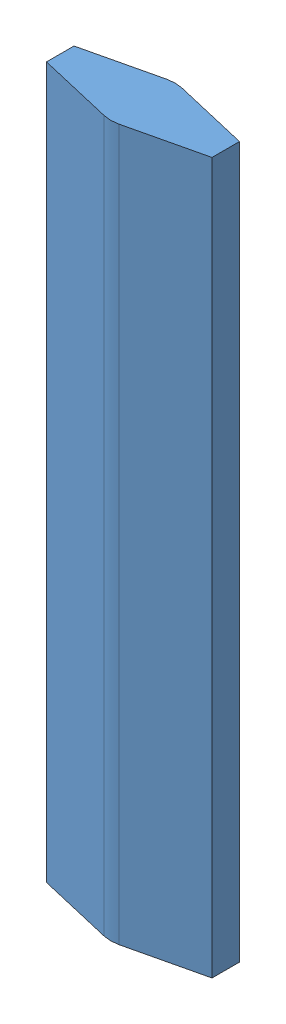
SolidWorks assembly String-III, configuration 默认. Lengths in mm.
Overall size (538.95 1520 404.36).
161 component instances, 6 part files, 3 mates.
Components (placement in the parent):
- StringBox-III-1: StringBox-III [默认] at (25.091 -857.2069 1520) size (354 1520 138)
- Unit-III-1: Unit-III [默认] at (25.091 -850.6069 1520) size (538.95 85.58 404.36)
  - OuterShell-III-1: OuterShell-III [默认] at origin size (538.95 73.59 404.36)
  - InnerUnit-1: InnerUnit [默认] at (-1.9481 30.6195 80) x (1 0 0) z (0 0 -1) size (102 85 103.7)
    - BEGeDet-2: BEGeDet [默认] at (1.9481 14.6195 80) x (1 0 0) z (0 0 -1) size (80 40 80)
    - InnerShell-3: InnerShell [默认] at (1.9481 -36.3805 80) size (102 61 102)
    - Electronics-1: Electronics [默认] at (1.9481 24.7195 80) x (-1 0 0) z (0 0 1) size (21.21 85 103.7)
  - SiPMArray-1: SiPMArray [默认] at (165 35.3248 0) size (10.4 81 40.4)
  - SiPMArray-2: SiPMArray [默认] at (-165 35.3248 0) x (-1 0 0) z (0 0 -1) size (10.4 81 40.4)
- Unit-III-2: Unit-III [默认] at (25.091 -778.6069 1520) size (538.95 85.58 404.36)
  - OuterShell-III-1: OuterShell-III [默认] at origin size (538.95 73.59 404.36)
  - InnerUnit-1: InnerUnit [默认] at (-1.9481 30.6195 80) x (1 0 0) z (0 0 -1) size (102 85 103.7)
    - BEGeDet-2: BEGeDet [默认] at (1.9481 14.6195 80) x (1 0 0) z (0 0 -1) size (80 40 80)
    - InnerShell-3: InnerShell [默认] at (1.9481 -36.3805 80) size (102 61 102)
    - Electronics-1: Electronics [默认] at (1.9481 24.7195 80) x (-1 0 0) z (0 0 1) size (21.21 85 103.7)
  - SiPMArray-1: SiPMArray [默认] at (165 35.3248 0) size (10.4 81 40.4)
  - SiPMArray-2: SiPMArray [默认] at (-165 35.3248 0) x (-1 0 0) z (0 0 -1) size (10.4 81 40.4)
- Unit-III-3: Unit-III [默认] at (25.091 -706.6069 1520) size (538.95 85.58 404.36)
  - OuterShell-III-1: OuterShell-III [默认] at origin size (538.95 73.59 404.36)
  - InnerUnit-1: InnerUnit [默认] at (-1.9481 30.6195 80) x (1 0 0) z (0 0 -1) size (102 85 103.7)
    - BEGeDet-2: BEGeDet [默认] at (1.9481 14.6195 80) x (1 0 0) z (0 0 -1) size (80 40 80)
    - InnerShell-3: InnerShell [默认] at (1.9481 -36.3805 80) size (102 61 102)
    - Electronics-1: Electronics [默认] at (1.9481 24.7195 80) x (-1 0 0) z (0 0 1) size (21.21 85 103.7)
  - SiPMArray-1: SiPMArray [默认] at (165 35.3248 0) size (10.4 81 40.4)
  - SiPMArray-2: SiPMArray [默认] at (-165 35.3248 0) x (-1 0 0) z (0 0 -1) size (10.4 81 40.4)
- Unit-III-4: Unit-III [默认] at (25.091 -634.6069 1520) size (538.95 85.58 404.36)
  - OuterShell-III-1: OuterShell-III [默认] at origin size (538.95 73.59 404.36)
  - InnerUnit-1: InnerUnit [默认] at (-1.9481 30.6195 80) x (1 0 0) z (0 0 -1) size (102 85 103.7)
    - BEGeDet-2: BEGeDet [默认] at (1.9481 14.6195 80) x (1 0 0) z (0 0 -1) size (80 40 80)
    - InnerShell-3: InnerShell [默认] at (1.9481 -36.3805 80) size (102 61 102)
    - Electronics-1: Electronics [默认] at (1.9481 24.7195 80) x (-1 0 0) z (0 0 1) size (21.21 85 103.7)
  - SiPMArray-1: SiPMArray [默认] at (165 35.3248 0) size (10.4 81 40.4)
  - SiPMArray-2: SiPMArray [默认] at (-165 35.3248 0) x (-1 0 0) z (0 0 -1) size (10.4 81 40.4)
- Unit-III-5: Unit-III [默认] at (25.091 -562.6069 1520) size (538.95 85.58 404.36)
  - OuterShell-III-1: OuterShell-III [默认] at origin size (538.95 73.59 404.36)
  - InnerUnit-1: InnerUnit [默认] at (-1.9481 30.6195 80) x (1 0 0) z (0 0 -1) size (102 85 103.7)
    - BEGeDet-2: BEGeDet [默认] at (1.9481 14.6195 80) x (1 0 0) z (0 0 -1) size (80 40 80)
    - InnerShell-3: InnerShell [默认] at (1.9481 -36.3805 80) size (102 61 102)
    - Electronics-1: Electronics [默认] at (1.9481 24.7195 80) x (-1 0 0) z (0 0 1) size (21.21 85 103.7)
  - SiPMArray-1: SiPMArray [默认] at (165 35.3248 0) size (10.4 81 40.4)
  - SiPMArray-2: SiPMArray [默认] at (-165 35.3248 0) x (-1 0 0) z (0 0 -1) size (10.4 81 40.4)
- Unit-III-6: Unit-III [默认] at (25.091 -490.6069 1520) size (538.95 85.58 404.36)
  - OuterShell-III-1: OuterShell-III [默认] at origin size (538.95 73.59 404.36)
  - InnerUnit-1: InnerUnit [默认] at (-1.9481 30.6195 80) x (1 0 0) z (0 0 -1) size (102 85 103.7)
    - BEGeDet-2: BEGeDet [默认] at (1.9481 14.6195 80) x (1 0 0) z (0 0 -1) size (80 40 80)
    - InnerShell-3: InnerShell [默认] at (1.9481 -36.3805 80) size (102 61 102)
    - Electronics-1: Electronics [默认] at (1.9481 24.7195 80) x (-1 0 0) z (0 0 1) size (21.21 85 103.7)
  - SiPMArray-1: SiPMArray [默认] at (165 35.3248 0) size (10.4 81 40.4)
  - SiPMArray-2: SiPMArray [默认] at (-165 35.3248 0) x (-1 0 0) z (0 0 -1) size (10.4 81 40.4)
- Unit-III-7: Unit-III [默认] at (25.091 -418.6069 1520) size (538.95 85.58 404.36)
  - OuterShell-III-1: OuterShell-III [默认] at origin size (538.95 73.59 404.36)
  - InnerUnit-1: InnerUnit [默认] at (-1.9481 30.6195 80) x (1 0 0) z (0 0 -1) size (102 85 103.7)
    - BEGeDet-2: BEGeDet [默认] at (1.9481 14.6195 80) x (1 0 0) z (0 0 -1) size (80 40 80)
    - InnerShell-3: InnerShell [默认] at (1.9481 -36.3805 80) size (102 61 102)
    - Electronics-1: Electronics [默认] at (1.9481 24.7195 80) x (-1 0 0) z (0 0 1) size (21.21 85 103.7)
  - SiPMArray-1: SiPMArray [默认] at (165 35.3248 0) size (10.4 81 40.4)
  - SiPMArray-2: SiPMArray [默认] at (-165 35.3248 0) x (-1 0 0) z (0 0 -1) size (10.4 81 40.4)
- Unit-III-8: Unit-III [默认] at (25.091 -346.6069 1520) size (538.95 85.58 404.36)
  - OuterShell-III-1: OuterShell-III [默认] at origin size (538.95 73.59 404.36)
  - InnerUnit-1: InnerUnit [默认] at (-1.9481 30.6195 80) x (1 0 0) z (0 0 -1) size (102 85 103.7)
    - BEGeDet-2: BEGeDet [默认] at (1.9481 14.6195 80) x (1 0 0) z (0 0 -1) size (80 40 80)
    - InnerShell-3: InnerShell [默认] at (1.9481 -36.3805 80) size (102 61 102)
    - Electronics-1: Electronics [默认] at (1.9481 24.7195 80) x (-1 0 0) z (0 0 1) size (21.21 85 103.7)
  - SiPMArray-1: SiPMArray [默认] at (165 35.3248 0) size (10.4 81 40.4)
  - SiPMArray-2: SiPMArray [默认] at (-165 35.3248 0) x (-1 0 0) z (0 0 -1) size (10.4 81 40.4)
- Unit-III-9: Unit-III [默认] at (25.091 -274.6069 1520) size (538.95 85.58 404.36)
  - OuterShell-III-1: OuterShell-III [默认] at origin size (538.95 73.59 404.36)
  - InnerUnit-1: InnerUnit [默认] at (-1.9481 30.6195 80) x (1 0 0) z (0 0 -1) size (102 85 103.7)
    - BEGeDet-2: BEGeDet [默认] at (1.9481 14.6195 80) x (1 0 0) z (0 0 -1) size (80 40 80)
    - InnerShell-3: InnerShell [默认] at (1.9481 -36.3805 80) size (102 61 102)
    - Electronics-1: Electronics [默认] at (1.9481 24.7195 80) x (-1 0 0) z (0 0 1) size (21.21 85 103.7)
  - SiPMArray-1: SiPMArray [默认] at (165 35.3248 0) size (10.4 81 40.4)
  - SiPMArray-2: SiPMArray [默认] at (-165 35.3248 0) x (-1 0 0) z (0 0 -1) size (10.4 81 40.4)
- Unit-III-10: Unit-III [默认] at (25.091 -202.6069 1520) size (538.95 85.58 404.36)
  - OuterShell-III-1: OuterShell-III [默认] at origin size (538.95 73.59 404.36)
  - InnerUnit-1: InnerUnit [默认] at (-1.9481 30.6195 80) x (1 0 0) z (0 0 -1) size (102 85 103.7)
    - BEGeDet-2: BEGeDet [默认] at (1.9481 14.6195 80) x (1 0 0) z (0 0 -1) size (80 40 80)
    - InnerShell-3: InnerShell [默认] at (1.9481 -36.3805 80) size (102 61 102)
    - Electronics-1: Electronics [默认] at (1.9481 24.7195 80) x (-1 0 0) z (0 0 1) size (21.21 85 103.7)
  - SiPMArray-1: SiPMArray [默认] at (165 35.3248 0) size (10.4 81 40.4)
  - SiPMArray-2: SiPMArray [默认] at (-165 35.3248 0) x (-1 0 0) z (0 0 -1) size (10.4 81 40.4)
- Unit-III-11: Unit-III [默认] at (25.091 -130.6069 1520) size (538.95 85.58 404.36)
  - OuterShell-III-1: OuterShell-III [默认] at origin size (538.95 73.59 404.36)
  - InnerUnit-1: InnerUnit [默认] at (-1.9481 30.6195 80) x (1 0 0) z (0 0 -1) size (102 85 103.7)
    - BEGeDet-2: BEGeDet [默认] at (1.9481 14.6195 80) x (1 0 0) z (0 0 -1) size (80 40 80)
    - InnerShell-3: InnerShell [默认] at (1.9481 -36.3805 80) size (102 61 102)
    - Electronics-1: Electronics [默认] at (1.9481 24.7195 80) x (-1 0 0) z (0 0 1) size (21.21 85 103.7)
  - SiPMArray-1: SiPMArray [默认] at (165 35.3248 0) size (10.4 81 40.4)
  - SiPMArray-2: SiPMArray [默认] at (-165 35.3248 0) x (-1 0 0) z (0 0 -1) size (10.4 81 40.4)
- Unit-III-12: Unit-III [默认] at (25.091 -58.6069 1520) size (538.95 85.58 404.36)
  - OuterShell-III-1: OuterShell-III [默认] at origin size (538.95 73.59 404.36)
  - InnerUnit-1: InnerUnit [默认] at (-1.9481 30.6195 80) x (1 0 0) z (0 0 -1) size (102 85 103.7)
    - BEGeDet-2: BEGeDet [默认] at (1.9481 14.6195 80) x (1 0 0) z (0 0 -1) size (80 40 80)
    - InnerShell-3: InnerShell [默认] at (1.9481 -36.3805 80) size (102 61 102)
    - Electronics-1: Electronics [默认] at (1.9481 24.7195 80) x (-1 0 0) z (0 0 1) size (21.21 85 103.7)
  - SiPMArray-1: SiPMArray [默认] at (165 35.3248 0) size (10.4 81 40.4)
  - SiPMArray-2: SiPMArray [默认] at (-165 35.3248 0) x (-1 0 0) z (0 0 -1) size (10.4 81 40.4)
- Unit-III-13: Unit-III [默认] at (25.091 13.3931 1520) size (538.95 85.58 404.36)
  - OuterShell-III-1: OuterShell-III [默认] at origin size (538.95 73.59 404.36)
  - InnerUnit-1: InnerUnit [默认] at (-1.9481 30.6195 80) x (1 0 0) z (0 0 -1) size (102 85 103.7)
    - BEGeDet-2: BEGeDet [默认] at (1.9481 14.6195 80) x (1 0 0) z (0 0 -1) size (80 40 80)
    - InnerShell-3: InnerShell [默认] at (1.9481 -36.3805 80) size (102 61 102)
    - Electronics-1: Electronics [默认] at (1.9481 24.7195 80) x (-1 0 0) z (0 0 1) size (21.21 85 103.7)
  - SiPMArray-1: SiPMArray [默认] at (165 35.3248 0) size (10.4 81 40.4)
  - SiPMArray-2: SiPMArray [默认] at (-165 35.3248 0) x (-1 0 0) z (0 0 -1) size (10.4 81 40.4)
- Unit-III-14: Unit-III [默认] at (25.091 85.3931 1520) size (538.95 85.58 404.36)
  - OuterShell-III-1: OuterShell-III [默认] at origin size (538.95 73.59 404.36)
  - InnerUnit-1: InnerUnit [默认] at (-1.9481 30.6195 80) x (1 0 0) z (0 0 -1) size (102 85 103.7)
    - BEGeDet-2: BEGeDet [默认] at (1.9481 14.6195 80) x (1 0 0) z (0 0 -1) size (80 40 80)
    - InnerShell-3: InnerShell [默认] at (1.9481 -36.3805 80) size (102 61 102)
    - Electronics-1: Electronics [默认] at (1.9481 24.7195 80) x (-1 0 0) z (0 0 1) size (21.21 85 103.7)
  - SiPMArray-1: SiPMArray [默认] at (165 35.3248 0) size (10.4 81 40.4)
  - SiPMArray-2: SiPMArray [默认] at (-165 35.3248 0) x (-1 0 0) z (0 0 -1) size (10.4 81 40.4)
- Unit-III-15: Unit-III [默认] at (25.091 157.3931 1520) size (538.95 85.58 404.36)
  - OuterShell-III-1: OuterShell-III [默认] at origin size (538.95 73.59 404.36)
  - InnerUnit-1: InnerUnit [默认] at (-1.9481 30.6195 80) x (1 0 0) z (0 0 -1) size (102 85 103.7)
    - BEGeDet-2: BEGeDet [默认] at (1.9481 14.6195 80) x (1 0 0) z (0 0 -1) size (80 40 80)
    - InnerShell-3: InnerShell [默认] at (1.9481 -36.3805 80) size (102 61 102)
    - Electronics-1: Electronics [默认] at (1.9481 24.7195 80) x (-1 0 0) z (0 0 1) size (21.21 85 103.7)
  - SiPMArray-1: SiPMArray [默认] at (165 35.3248 0) size (10.4 81 40.4)
  - SiPMArray-2: SiPMArray [默认] at (-165 35.3248 0) x (-1 0 0) z (0 0 -1) size (10.4 81 40.4)
- Unit-III-16: Unit-III [默认] at (25.091 229.3931 1520) size (538.95 85.58 404.36)
  - OuterShell-III-1: OuterShell-III [默认] at origin size (538.95 73.59 404.36)
  - InnerUnit-1: InnerUnit [默认] at (-1.9481 30.6195 80) x (1 0 0) z (0 0 -1) size (102 85 103.7)
    - BEGeDet-2: BEGeDet [默认] at (1.9481 14.6195 80) x (1 0 0) z (0 0 -1) size (80 40 80)
    - InnerShell-3: InnerShell [默认] at (1.9481 -36.3805 80) size (102 61 102)
    - Electronics-1: Electronics [默认] at (1.9481 24.7195 80) x (-1 0 0) z (0 0 1) size (21.21 85 103.7)
  - SiPMArray-1: SiPMArray [默认] at (165 35.3248 0) size (10.4 81 40.4)
  - SiPMArray-2: SiPMArray [默认] at (-165 35.3248 0) x (-1 0 0) z (0 0 -1) size (10.4 81 40.4)
- Unit-III-17: Unit-III [默认] at (25.091 301.3931 1520) size (538.95 85.58 404.36)
  - OuterShell-III-1: OuterShell-III [默认] at origin size (538.95 73.59 404.36)
  - InnerUnit-1: InnerUnit [默认] at (-1.9481 30.6195 80) x (1 0 0) z (0 0 -1) size (102 85 103.7)
    - BEGeDet-2: BEGeDet [默认] at (1.9481 14.6195 80) x (1 0 0) z (0 0 -1) size (80 40 80)
    - InnerShell-3: InnerShell [默认] at (1.9481 -36.3805 80) size (102 61 102)
    - Electronics-1: Electronics [默认] at (1.9481 24.7195 80) x (-1 0 0) z (0 0 1) size (21.21 85 103.7)
  - SiPMArray-1: SiPMArray [默认] at (165 35.3248 0) size (10.4 81 40.4)
  - SiPMArray-2: SiPMArray [默认] at (-165 35.3248 0) x (-1 0 0) z (0 0 -1) size (10.4 81 40.4)
- Unit-III-18: Unit-III [默认] at (25.091 373.3931 1520) size (538.95 85.58 404.36)
  - OuterShell-III-1: OuterShell-III [默认] at origin size (538.95 73.59 404.36)
  - InnerUnit-1: InnerUnit [默认] at (-1.9481 30.6195 80) x (1 0 0) z (0 0 -1) size (102 85 103.7)
    - BEGeDet-2: BEGeDet [默认] at (1.9481 14.6195 80) x (1 0 0) z (0 0 -1) size (80 40 80)
    - InnerShell-3: InnerShell [默认] at (1.9481 -36.3805 80) size (102 61 102)
    - Electronics-1: Electronics [默认] at (1.9481 24.7195 80) x (-1 0 0) z (0 0 1) size (21.21 85 103.7)
  - SiPMArray-1: SiPMArray [默认] at (165 35.3248 0) size (10.4 81 40.4)
  - SiPMArray-2: SiPMArray [默认] at (-165 35.3248 0) x (-1 0 0) z (0 0 -1) size (10.4 81 40.4)
- Unit-III-19: Unit-III [默认] at (25.091 445.3931 1520) size (538.95 85.58 404.36)
  - OuterShell-III-1: OuterShell-III [默认] at origin size (538.95 73.59 404.36)
  - InnerUnit-1: InnerUnit [默认] at (-1.9481 30.6195 80) x (1 0 0) z (0 0 -1) size (102 85 103.7)
    - BEGeDet-2: BEGeDet [默认] at (1.9481 14.6195 80) x (1 0 0) z (0 0 -1) size (80 40 80)
    - InnerShell-3: InnerShell [默认] at (1.9481 -36.3805 80) size (102 61 102)
    - Electronics-1: Electronics [默认] at (1.9481 24.7195 80) x (-1 0 0) z (0 0 1) size (21.21 85 103.7)
  - SiPMArray-1: SiPMArray [默认] at (165 35.3248 0) size (10.4 81 40.4)
  - SiPMArray-2: SiPMArray [默认] at (-165 35.3248 0) x (-1 0 0) z (0 0 -1) size (10.4 81 40.4)
- Unit-III-20: Unit-III [默认] at (25.091 517.3931 1520) size (538.95 85.58 404.36)
  - OuterShell-III-1: OuterShell-III [默认] at origin size (538.95 73.59 404.36)
  - InnerUnit-1: InnerUnit [默认] at (-1.9481 30.6195 80) x (1 0 0) z (0 0 -1) size (102 85 103.7)
    - BEGeDet-2: BEGeDet [默认] at (1.9481 14.6195 80) x (1 0 0) z (0 0 -1) size (80 40 80)
    - InnerShell-3: InnerShell [默认] at (1.9481 -36.3805 80) size (102 61 102)
    - Electronics-1: Electronics [默认] at (1.9481 24.7195 80) x (-1 0 0) z (0 0 1) size (21.21 85 103.7)
  - SiPMArray-1: SiPMArray [默认] at (165 35.3248 0) size (10.4 81 40.4)
  - SiPMArray-2: SiPMArray [默认] at (-165 35.3248 0) x (-1 0 0) z (0 0 -1) size (10.4 81 40.4)
Mates (geometry in assembly coordinates):
- 重合2: coincident anti-aligned: plane of StringBox-III-1 through (25.091 -857.2069 1520) normal (0 1 0); plane of Unit-III-1/InnerUnit-1/Electronics-1 through (25.091 -857.2069 1571.35) normal (0 -1 0)
- 同心2: concentric aligned: circle of StringBox-III-1; circle of Unit-III-1/InnerUnit-1/BEGeDet-2
- 平行1: parallel aligned: plane of StringBox-III-1 through (202.091 642.7931 1541.49) normal (1 0 0); plane of Unit-III-1/OuterShell-III-1 through (190.091 -698.6069 1539.9043) normal (1 0 0)
